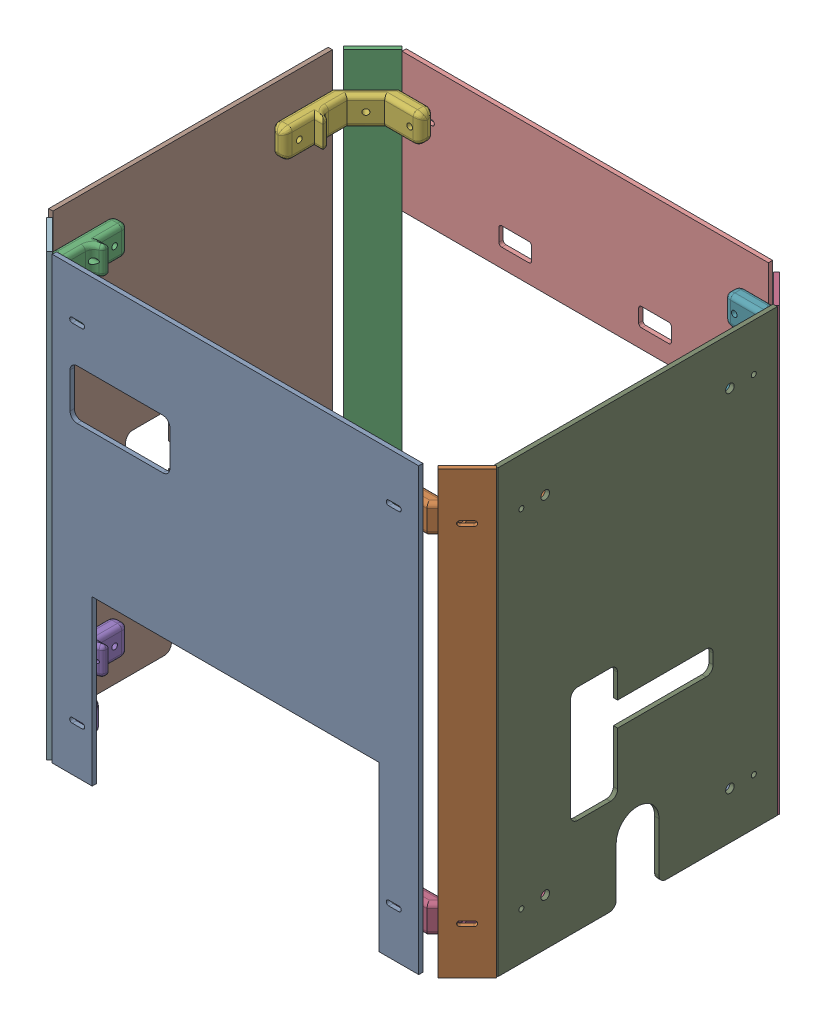
SolidWorks assembly Assemblage_Plexi_V2, configuration Défaut. Lengths in mm.
Overall size (315.21 309 249.4).
16 component instances, 6 part files, 49 mates.
Components (placement in the parent):
- Plexi_Arriere_V2-1: Plexi_Arriere_V2 [Défaut] at (-7.619 -2.2409 -1.5) size (257 309 3)
- Support_Plexi-1: Support_Plexi [Défaut] at (136.8892 119.2591 -58.2) x (0 0 -1) z (1 0 0) size (66.7 20 48.2)
- Support_Plexi-2: Support_Plexi [Défaut] at (-152.0766 119.2591 -58.2) x (0 0 -1) z (-1 0 0) size (66.7 20 48.2)
- Support_Plexi-3: Support_Plexi [Défaut] at (136.8892 -123.7409 -58.2) x (0 0 -1) z (1 0 0) size (66.7 20 48.2)
- Support_Plexi-4: Support_Plexi [Défaut] at (-152.0766 -123.7409 -58.2) x (0 0 -1) z (-1 0 0) size (66.7 20 48.2)
- Support_Plexi-5: Support_Plexi [Défaut] at (-152.0766 119.2591 -187.7) x (0 0 1) z (-1 0 0) size (66.7 20 48.2)
- Support_Plexi-6: Support_Plexi [Défaut] at (136.8892 119.2591 -187.7) x (0 0 1) z (1 0 0) size (66.7 20 48.2)
- Plexi_Cote_V2-1: Plexi_Cote_V2 [Défaut] at (-162.0766 -2.2409 -122.95) x (0 0 1) z (-1 0 0) size (196 309 3)
- Plexi_Cote_V2-2: Plexi_Cote_V2 [Défaut] at (149.8892 -2.2409 -122.95) x (0 0 1) z (-1 0 0) size (196 309 3)
- Plexi_Avant_V2-1: Plexi_Avant_V2 [Défaut] at (-8.3108 103.7591 -247.4) size (257 97 3)
- Support_Plexi_2-1: Support_Plexi_2 [Défaut] at (-152.0766 -123.7409 -187.7) x (0 0 1) z (-1 0 0) size (61.67 20 21)
- Plexi_Angle_V2-1: Plexi_Angle_V2 [Défaut] at (-148.0017 -2.2409 -10.6251) x (0.707107 0 0.707107) z (-0.707107 0 0.707107) size (29 309 3)
- Support_Plexi_2-2: Support_Plexi_2 [Défaut] at (136.8892 -123.7409 -187.7) x (0 0 1) z (1 0 0) size (61.67 20 21)
- Plexi_Angle_V2-2: Plexi_Angle_V2 [Défaut] at (137.764 -2.2409 -15.5749) x (0.707107 0 -0.707107) z (0.707107 0 0.707107) size (29 309 3)
- Plexi_Angle_V2-3: Plexi_Angle_V2 [Défaut] at (-150.123 -2.2409 -237.3962) x (0.707107 0 -0.707107) z (0.707107 0 0.707107) size (29 309 3)
- Plexi_Angle_V2-4: Plexi_Angle_V2 [Défaut] at (139.8853 -2.2409 -232.4464) x (0.707107 0 0.707107) z (-0.707107 0 0.707107) size (29 309 3)
Mates (geometry in assembly coordinates):
- Rainure2: slot: cylinder of Support_Plexi-1 through (106.1892 119.2591 -68.201) axis (0 0 1) radius 2; cylinder of Plexi_Arriere_V2-1 through (106.881 119.2591 1.5) axis (0 0 -1) radius 1.75; cylinder of Plexi_Arriere_V2-1 through (99.881 119.2591 1.5) axis (0 0 -1) radius 1.75
- Rainure3: slot: cylinder of Support_Plexi-2 through (-121.3766 119.2591 -68.201) axis (0 0 1) radius 2; plane of Plexi_Arriere_V2-1 through (-122.119 117.5091 1.5) normal (0 1 0); cylinder of Plexi_Arriere_V2-1 through (-122.119 119.2591 1.5) axis (0 0 -1) radius 1.75
- Rainure4: slot: cylinder of Support_Plexi-4 through (-121.3766 -123.7409 -68.201) axis (0 0 1) radius 2; plane of Plexi_Arriere_V2-1 through (-122.119 -125.4909 1.5) normal (0 1 0); cylinder of Plexi_Arriere_V2-1 through (-122.119 -123.7409 1.5) axis (0 0 -1) radius 1.75
- Rainure6: slot: plane of Plexi_Arriere_V2-1 through (99.881 -125.4909 1.5) normal (0 1 0); cylinder of Support_Plexi-3 through (106.1892 -123.7409 -68.201) axis (0 0 1) radius 2; cylinder of Plexi_Arriere_V2-1 through (99.881 -123.7409 1.5) axis (0 0 -1) radius 1.75
- Coïncidente1: coincident anti-aligned: plane of Plexi_Arriere_V2-1 through (-7.619 -2.2409 -1.5) normal (0 0 -1); plane of Support_Plexi-3 through (98.6892 -133.7409 -1.5) normal (0 0 1)
- Coïncidente2: coincident anti-aligned: plane of Plexi_Arriere_V2-1 through (-7.619 -2.2409 -1.5) normal (0 0 -1); plane of Support_Plexi-2 through (-113.8766 129.2591 -1.5) normal (0 0 1)
- Coïncidente3: coincident anti-aligned: plane of Plexi_Arriere_V2-1 through (-7.619 -2.2409 -1.5) normal (0 0 -1); plane of Support_Plexi-1 through (98.6892 109.2591 -1.5) normal (0 0 1)
- Coïncidente4: coincident anti-aligned: plane of Plexi_Arriere_V2-1 through (-7.619 -2.2409 -1.5) normal (0 0 -1); plane of Support_Plexi-4 through (-113.8766 -113.7409 -1.5) normal (0 0 1)
- Coïncidente5: coincident aligned: plane of Support_Plexi-1 through (139.8892 129.2591 -68.2) normal (0 1 0); plane of Support_Plexi-2 through (-155.0766 129.2591 -68.2) normal (0 1 0)
- Coïncidente6: coincident aligned: plane of Support_Plexi-3 through (139.8892 -113.7409 -68.2) normal (0 1 0); plane of Support_Plexi-4 through (-155.0766 -113.7409 -68.2) normal (0 1 0)
- Coïncidente7: coincident anti-aligned: plane of Support_Plexi-1 through (146.8892 119.2591 -58.2) normal (1 0 0); plane of Plexi_Cote_V2-2 through (146.8892 -2.2409 -122.95) normal (-1 0 0)
- Coaxiale2: concentric aligned: cylinder of Support_Plexi-1 through (98.6882 119.2591 -41.45) axis (1 0 0) radius 2; cylinder of Plexi_Cote_V2-2 through (146.8892 119.2591 -41.45) axis (1 0 0) radius 1.75
- Coaxiale3: concentric anti-aligned: cylinder of Support_Plexi-1 through (146.8892 119.2591 -58.2) axis (-1 0 0) radius 3; cylinder of Plexi_Cote_V2-2 through (146.8892 119.2591 -58.2) axis (1 0 0) radius 3
- Coaxiale4: concentric aligned: cylinder of Support_Plexi-3 through (98.6882 -123.7409 -41.45) axis (1 0 0) radius 2; cylinder of Plexi_Cote_V2-2 through (146.8892 -123.7409 -41.45) axis (1 0 0) radius 1.75
- Coaxiale5: concentric anti-aligned: cylinder of Support_Plexi-3 through (146.8892 -123.7409 -58.2) axis (-1 0 0) radius 3; cylinder of Plexi_Cote_V2-2 through (146.8892 -123.7409 -58.2) axis (1 0 0) radius 3
- Coaxiale6: concentric anti-aligned: cylinder of Support_Plexi-2 through (-113.8756 119.2591 -41.45) axis (-1 0 0) radius 2; cylinder of Plexi_Cote_V2-1 through (-165.0766 119.2591 -41.45) axis (1 0 0) radius 1.75
- Coaxiale7: concentric aligned: cylinder of Support_Plexi-2 through (-162.0766 119.2591 -58.2) axis (1 0 0) radius 3; cylinder of Plexi_Cote_V2-1 through (-165.0766 119.2591 -58.2) axis (1 0 0) radius 3
- Coïncidente8: coincident anti-aligned: plane of Support_Plexi-2 through (-162.0766 119.2591 -58.2) normal (-1 0 0); plane of Plexi_Cote_V2-1 through (-162.0766 -2.2409 -122.95) normal (1 0 0)
- Coaxiale8: concentric anti-aligned: cylinder of Support_Plexi-4 through (-113.8756 -123.7409 -41.45) axis (-1 0 0) radius 2; cylinder of Plexi_Cote_V2-1 through (-165.0766 -123.7409 -41.45) axis (1 0 0) radius 1.75
- Coaxiale9: concentric aligned: cylinder of Support_Plexi-4 through (-162.0766 -123.7409 -58.2) axis (1 0 0) radius 3; cylinder of Plexi_Cote_V2-1 through (-165.0766 -123.7409 -58.2) axis (1 0 0) radius 3
- Coïncidente9: coincident anti-aligned: plane of Support_Plexi-4 through (-162.0766 -123.7409 -58.2) normal (-1 0 0); plane of Plexi_Cote_V2-1 through (-162.0766 -2.2409 -122.95) normal (1 0 0)
- Coïncidente10: coincident anti-aligned: plane of Support_Plexi-3 through (146.8892 -123.7409 -58.2) normal (1 0 0); plane of Plexi_Cote_V2-2 through (146.8892 -2.2409 -122.95) normal (-1 0 0)
- Coaxiale10: concentric anti-aligned: cylinder of Support_Plexi-5 through (-113.8756 119.2591 -204.45) axis (-1 0 0) radius 2; cylinder of Plexi_Cote_V2-1 through (-165.0766 119.2591 -204.45) axis (1 0 0) radius 1.75
- Coaxiale11: concentric aligned: cylinder of Support_Plexi-5 through (-162.0766 119.2591 -187.7) axis (1 0 0) radius 3; cylinder of Plexi_Cote_V2-1 through (-165.0766 119.2591 -187.7) axis (1 0 0) radius 3
- Coïncidente11: coincident anti-aligned: plane of Plexi_Cote_V2-1 through (-162.0766 -2.2409 -122.95) normal (1 0 0); plane of Support_Plexi-5 through (-162.0766 119.2591 -187.7) normal (-1 0 0)
- Coaxiale12: concentric aligned: cylinder of Support_Plexi-6 through (98.6882 119.2591 -204.45) axis (1 0 0) radius 2; cylinder of Plexi_Cote_V2-2 through (146.8892 119.2591 -204.45) axis (1 0 0) radius 1.75
- Coaxiale13: concentric anti-aligned: cylinder of Support_Plexi-6 through (146.8892 119.2591 -187.7) axis (-1 0 0) radius 3; cylinder of Plexi_Cote_V2-2 through (146.8892 119.2591 -187.7) axis (1 0 0) radius 3
- Coïncidente12: coincident anti-aligned: plane of Support_Plexi-6 through (146.8892 119.2591 -187.7) normal (1 0 0); plane of Plexi_Cote_V2-2 through (146.8892 -2.2409 -122.95) normal (-1 0 0)
- Rainure7: slot: plane of Plexi_Avant_V2-1 through (99.1892 117.5091 -244.4) normal (0 1 0); cylinder of Support_Plexi-6 through (106.1892 119.2591 -177.699) axis (0 0 -1) radius 2; cylinder of Plexi_Avant_V2-1 through (99.1892 119.2591 -244.4) axis (0 0 -1) radius 1.75
- Rainure8: slot: cylinder of Support_Plexi-5 through (-121.3766 119.2591 -177.699) axis (0 0 -1) radius 2; plane of Plexi_Avant_V2-1 through (-122.8108 117.5091 -244.4) normal (0 1 0); cylinder of Plexi_Avant_V2-1 through (-122.8108 119.2591 -244.4) axis (0 0 -1) radius 1.75
- Coïncidente13: coincident anti-aligned: plane of Support_Plexi-5 through (-113.8766 109.2591 -244.4) normal (0 0 -1); plane of Plexi_Avant_V2-1 through (-8.3108 103.7591 -244.4) normal (0 0 1)
- Coaxiale14: concentric anti-aligned: cylinder of Plexi_Cote_V2-2 through (146.8892 -123.7409 -187.7) axis (1 0 0) radius 3; cylinder of Support_Plexi_2-2 through (146.8892 -123.7409 -187.7) axis (-1 0 0) radius 3
- Coaxiale15: concentric aligned: cylinder of Plexi_Cote_V2-2 through (146.8892 -123.7409 -204.45) axis (1 0 0) radius 1.75; cylinder of Support_Plexi_2-2 through (98.6882 -123.7409 -204.45) axis (1 0 0) radius 2
- Coïncidente14: coincident anti-aligned: plane of Plexi_Cote_V2-2 through (146.8892 -2.2409 -122.95) normal (-1 0 0); plane of Support_Plexi_2-2 through (146.8892 -123.7409 -187.7) normal (1 0 0)
- Coaxiale16: concentric anti-aligned: cylinder of Plexi_Cote_V2-1 through (-165.0766 -123.7409 -204.45) axis (1 0 0) radius 1.75; cylinder of Support_Plexi_2-1 through (-113.8756 -123.7409 -204.45) axis (-1 0 0) radius 2
- Coaxiale17: concentric aligned: cylinder of Plexi_Cote_V2-1 through (-165.0766 -123.7409 -187.7) axis (1 0 0) radius 3; cylinder of Support_Plexi_2-1 through (-162.0766 -123.7409 -187.7) axis (1 0 0) radius 3
- Coïncidente15: coincident anti-aligned: plane of Plexi_Cote_V2-1 through (-162.0766 -2.2409 -122.95) normal (1 0 0); plane of Support_Plexi_2-1 through (-162.0766 -123.7409 -187.7) normal (-1 0 0)
- Rainure9: slot: plane of Plexi_Angle_V2-4 through (135.2892 117.5091 -232.8) normal (0 1 0); cylinder of Support_Plexi-6 through (89.4382 119.2591 -186.949) axis (0.707107 0 -0.707107) radius 2; cylinder of Plexi_Angle_V2-4 through (135.2892 119.2591 -232.8) axis (0.707107 0 -0.707107) radius 1.75
- Rainure10: slot: plane of Plexi_Angle_V2-4 through (135.2892 -125.4909 -232.8) normal (0 1 0); cylinder of Support_Plexi_2-2 through (89.4382 -123.7409 -186.949) axis (0.707107 0 -0.707107) radius 2; cylinder of Plexi_Angle_V2-4 through (135.2892 -123.7409 -232.8) axis (0.707107 0 -0.707107) radius 1.75
- Coïncidente16: coincident anti-aligned: plane of Support_Plexi_2-2 through (146.8892 -113.7409 -221.2) normal (0.707107 0 -0.707107); plane of Plexi_Angle_V2-4 through (137.764 -2.2409 -230.3251) normal (-0.707107 0 0.707107)
- Rainure11: slot: plane of Plexi_Angle_V2-3 through (-150.4766 117.5091 -232.8) normal (0 1 0); cylinder of Support_Plexi-5 through (-104.6256 119.2591 -186.949) axis (-0.707107 0 -0.707107) radius 2; cylinder of Plexi_Angle_V2-3 through (-150.4766 119.2591 -232.8) axis (-0.707107 0 -0.707107) radius 1.75
- Rainure12: slot: plane of Plexi_Angle_V2-3 through (-150.4766 -125.4909 -232.8) normal (0 1 0); cylinder of Support_Plexi_2-1 through (-104.6256 -123.7409 -186.949) axis (-0.707107 0 -0.707107) radius 2; cylinder of Plexi_Angle_V2-3 through (-150.4766 -123.7409 -232.8) axis (-0.707107 0 -0.707107) radius 1.75
- Coïncidente17: coincident anti-aligned: plane of Support_Plexi_2-1 through (-162.0766 -133.7409 -221.2) normal (-0.707107 0 -0.707107); plane of Plexi_Angle_V2-3 through (-148.0017 -2.2409 -235.2749) normal (0.707107 0 0.707107)
- Rainure14: slot: cylinder of Support_Plexi-1 through (89.4382 119.2591 -58.951) axis (0.707107 0 0.707107) radius 2; plane of Plexi_Angle_V2-2 through (137.4105 117.5091 -10.9787) normal (0 1 0); cylinder of ? through (123.6528 119.2591 -24.7364) axis (-0.707107 0 -0.707107) radius 1.75
- Rainure15: slot: plane of Plexi_Angle_V2-2 through (137.4105 -125.4909 -10.9787) normal (0 1 0); cylinder of Support_Plexi-3 through (89.4382 -123.7409 -58.951) axis (0.707107 0 0.707107) radius 2; cylinder of ? through (123.6528 -123.7409 -24.7364) axis (-0.707107 0 -0.707107) radius 1.75
- Rainure16: slot: plane of Plexi_Angle_V2-1 through (-152.5979 117.5091 -10.9787) normal (0 1 0); cylinder of Support_Plexi-2 through (-104.6256 119.2591 -58.951) axis (-0.707107 0 0.707107) radius 2; cylinder of Plexi_Angle_V2-1 through (-152.5979 119.2591 -10.9787) axis (0.707107 0 -0.707107) radius 1.75
- Rainure17: slot: plane of Plexi_Angle_V2-1 through (-152.5979 -125.4909 -10.9787) normal (0 1 0); cylinder of Support_Plexi-4 through (-104.6256 -123.7409 -58.951) axis (-0.707107 0 0.707107) radius 2; cylinder of Plexi_Angle_V2-1 through (-152.5979 -123.7409 -10.9787) axis (0.707107 0 -0.707107) radius 1.75
- Coïncidente18: coincident anti-aligned: plane of Support_Plexi-4 through (-162.0766 -113.7409 -24.7) normal (-0.707107 0 0.707107); plane of Plexi_Angle_V2-1 through (-148.0017 -2.2409 -10.6251) normal (0.707107 0 -0.707107)
- Coïncidente19: coincident anti-aligned: plane of Support_Plexi-3 through (146.8892 -133.7409 -24.7) normal (0.707107 0 0.707107); plane of Plexi_Angle_V2-2 through (137.764 -2.2409 -15.5749) normal (-0.707107 0 -0.707107)
